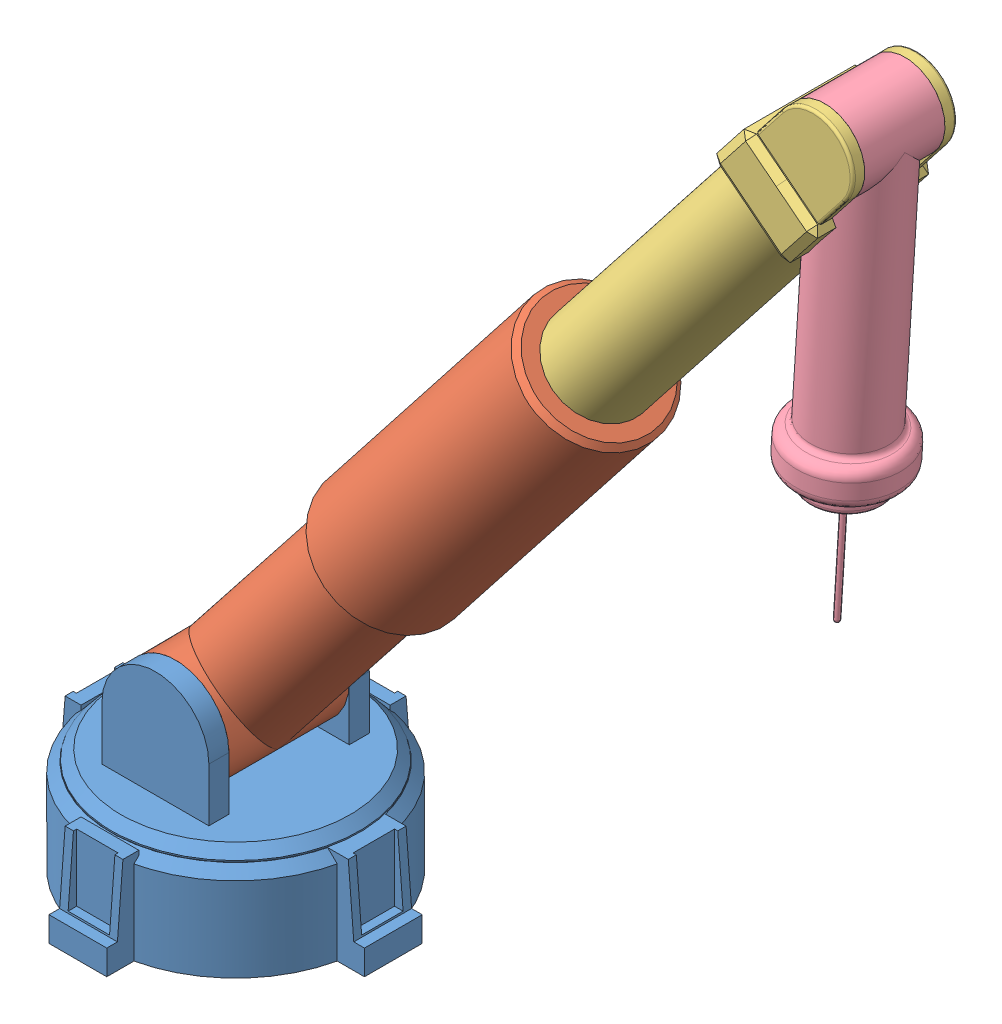
SolidWorks assembly Assem3, configuration Default. Lengths in mm.
Overall size (317.38 380.81 118).
4 component instances, 4 part files, 5 mates.
Components (placement in the parent):
- de-1: de [Default] at (-9.7383 21.364 119.4421) size (118 79 118)
- khau1-1: khau1 [Default] at (-9.7383 80.364 96.9421) x (0.785982 -0.618249 0) z (0 0 1) size (50 240 50)
- khau2-1: khau2 [Default] at (105.0516 226.2966 119.4421) x (0.785982 -0.618249 0) z (0 0 1) size (35 210 45)
- khau3-2: khau3 [Default] at (225.6102 379.5631 104.4421) x (-0.998021 0.062883 0) z (0 0 1) size (40 181 40)
Mates (geometry in assembly coordinates):
- Coincident1: coincident aligned: circle of de-1; circle of khau1-1
- Concentric1: concentric aligned: circle of khau1-1; circle of khau2-1
- Coincident3: coincident anti-aligned: line of khau1-1 through (41.2936 142.0061 99.9421) axis (0.618249 0.785982 0); line of khau2-1 through (146.8098 276.149 99.9421) axis (-0.618249 -0.785982 0)
- LimitDistance1: limit distance = 145.6692 mm aligned: plane of khau1-1 through (126.2766 253.2801 119.4421) normal (0.618249 0.785982 0); plane of khau2-1 through (230.0912 356.954 142.2811) normal (0.618249 0.785982 0)
- Coincident8: coincident anti-aligned: circle of khau2-1; circle of khau3-2
